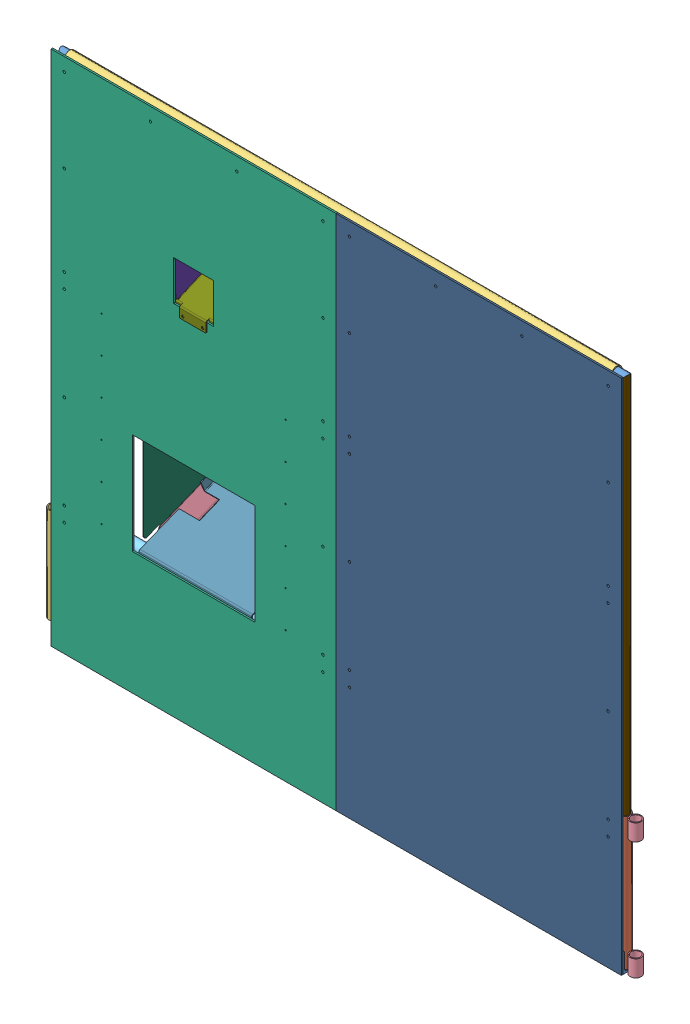
SolidWorks assembly GE-15001_ASM, configuration Default. Lengths in mm.
Overall size (2268.73 1981.2 780.07).
36 component instances, 21 part files, 0 mates.
Components (placement in the parent):
- GE-13015-L_ASM-1: GE-13015-L_ASM [Default] at origin size (2268.73 514.35 76.2)
  - GE-13015-01-1: GE-13015-01 [Default] x (1 0 0) z (0 -1 0) size (2184.4 76.2 76.2)
  - GE-13015-05-1: GE-13015-05 [Default] at (1071.118 260.35 -27.432) x (0 1 0) z (0 0 1) size (508 42.16 42.16)
  - GE-13015-05-2: GE-13015-05 [Default] at (-1071.118 260.35 -27.432) x (0 1 0) z (0 0 1) size (508 42.16 42.16)
  - GE-13015-04-1: GE-13015-04 [Default] at (-1113.282 252.4125 -27.432) x (0 1 0) z (0 0 1) size (365.12 42.16 42.16)
  - GE-13015-03-1: GE-13015-03 [Default] at (1113.282 482.6 -27.432) x (0 -1 0) z (0 0 1) size (63.5 42.16 42.16)
  - GE-13015-03-2: GE-13015-03 [Default] at (1113.282 31.75 -27.432) x (0 -1 0) z (0 0 1) size (63.5 42.16 42.16)
  - GE-13015-02-1: GE-13015-02 [Default] at (-1071.118 463.55 -27.432) size (2143.25 42.16 42.16)
- GE-15034_ASM-1: GE-15034_ASM [Default] at (-546.1 990.6 3.175) size (1092.2 1981.2 22.23)
  - GE-15003-1: GE-15003 [Default] at origin size (1092.2 1981.2 6.35)
  - GE-15037-1: GE-15037 [Default] at (352.425 -139.7 -12.7) x (-1 0 0) z (0 0 1) size (63.5 838.2 9.53)
  - GE-15037-2: GE-15037 [Default] at (-352.425 -139.7 -3.175) x (1 0 0) z (0 0 -1) size (63.5 838.2 9.53)
  - GE-15036-1: GE-15036 [Default] at (-339.725 -139.7 -19.05) size (50.8 723.9 6.35)
  - GE-15036-2: GE-15036 [Default] at (339.725 -139.7 -19.05) x (-1 0 0) z (0 0 1) size (50.8 723.9 6.35)
  - GE-15035-1: GE-15035 [Default] at (0 73.025 -6.35) x (-1 0 0) z (0 0 -1) size (676.27 412.75 6.35)
- GE-15002-1: GE-15002 [Default] at (546.1 990.6 3.175) size (1092.2 1981.2 6.35)
- GE-15004_ASM-1: GE-15004_ASM [Default] at (-546.1 4.6228 -122.9608) size (463.55 1141.84 780.07)
  - GE-15005-1: GE-15005 [Default] at origin size (457.2 14.29 63.5)
  - GE-15006-1: GE-15006 [Default] at (0 0 -288.925) size (50.8 4.62 641.35)
  - GE-15005-2: GE-15005 [Default] at (0 0 -577.85) size (457.2 14.29 63.5)
  - GE-15007-1: GE-15007 [Default] at (185.8772 0 40.9905) x (1 0 0) z (0 -1 0) size (85.44 660.4 764.01)
  - GE-15007-2: GE-15007 [Default] at (-185.8772 0 40.9905) x (1 0 0) z (0 -1 0) size (85.44 660.4 764.01)
  - GE-15008-1: GE-15008 [Default] at (0.2819 619.9194 -243.2609) x (1 0 0) z (0 -0.374607 0.927184) size (431.8 86.39 806.43)
  - GE-15009-1: GE-15009 [Default] at (-0.0025 453.7355 91.7786) x (1 0 0) z (0 -1 0) size (463.55 685.8 650.75)
- GE-15010-1: GE-15010 [Default] at (-546.1 1407.001 -72.0988) x (1 0 0) z (0 -0.920505 -0.390731) size (153.12 178.41 48.41)
- GE-15011-1: GE-15011 [Default] at (-546.1 1353.2065 -2.2473) x (1 0 0) z (0 -0.999848 -0.017452) size (158.75 152.4 234.67)
- GE-15012_ASM-1: GE-15012_ASM [Default] at (1071.118 6.35 -27.432) x (-1 0 0) z (0 0 -1) size (254 1968.5 33.4)
  - GE-15012-01-1: GE-15012-01 [Default] at origin size (33.4 1968.5 33.4)
  - GE-15012-02-1: GE-15012-02 [Default] at (-16.7005 1951.7995 0) size (254 33.4 33.4)
  - GE-15012-03-1: GE-15012-03 [Default] at (5.5245 1231.9 0) size (231.78 33.4 33.4)
- GE-15012_ASM-2: GE-15012_ASM [Default] at (-1071.118 6.35 -27.432) size (254 1968.5 33.4)
  - GE-15012-01-1: GE-15012-01 [Default] at origin size (33.4 1968.5 33.4)
  - GE-15012-02-1: GE-15012-02 [Default] at (-16.7005 1951.7995 0) size (254 33.4 33.4)
  - GE-15012-03-1: GE-15012-03 [Default] at (5.5245 1231.9 0) size (231.78 33.4 33.4)
- GE-15013-1: GE-15013 [Default] at (-1054.4175 1958.1495 -27.432) x (1 0 0) z (0 0 -1) size (2095.5 42.16 42.16)
- GE-15013-2: GE-15013 [Default] at (-1054.4175 1238.25 -27.432) x (1 0 0) z (0 0 -1) size (2095.5 42.16 42.16)
